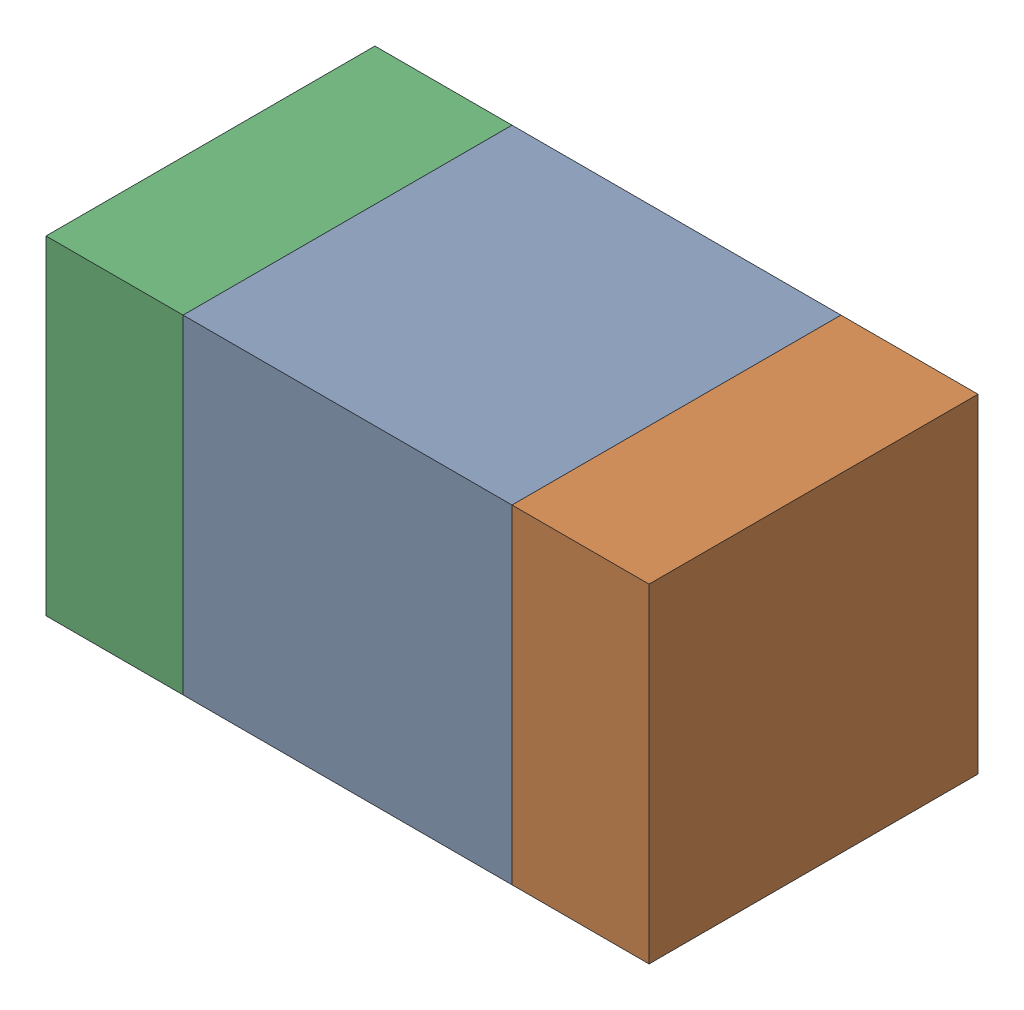
SolidWorks assembly C316_1PCB, configuration Default. Lengths in mm.
Overall size (1.1 0.6 0.6).
6 component instances, 2 part files, 0 mates.
Components (placement in the parent):
- 761606048-1: 761606048 [Default] at (131 108.8 -2.2638) size (0.6 0.6 0.6)
  - Extruded_9-1: Extruded_9 [Default] at origin size (0.6 0.6 0.6)
- 854785160-1: 854785160 [Default] at (131.425 108.8 -2.2638) size (0.25 0.6 0.6)
  - Extruded_19-1: Extruded_19 [Default] at origin size (0.25 0.6 0.6)
- 854785160-2: 854785160 [Default] at (130.575 108.8 -2.2638) size (0.25 0.6 0.6)
  - Extruded_19-1: Extruded_19 [Default] at origin size (0.25 0.6 0.6)
